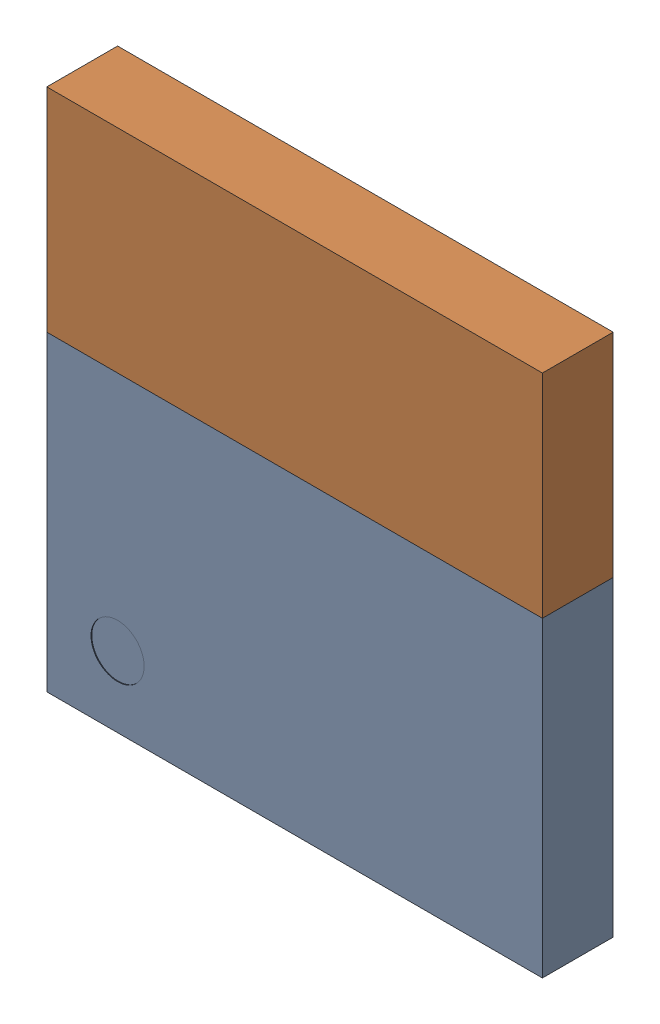
SolidWorks assembly U2, configuration Default. Lengths in mm.
Overall size (7 7.4 1).
3 component instances, 2 part files, 0 mates.
Components (placement in the parent):
- U2-subassembly-1-1: U2-subassembly-1 [Default] at (-4.5 13.125 0) x (1 0 0) z (0 -1 0) size (7 1 7.4)
  - Murata MBN52832-1: Murata MBN52832 [Default] at origin size (7 1 4.4)
  - Murata MBN52832-1-1: Murata MBN52832-1 [Default] at origin size (7 1 3)
